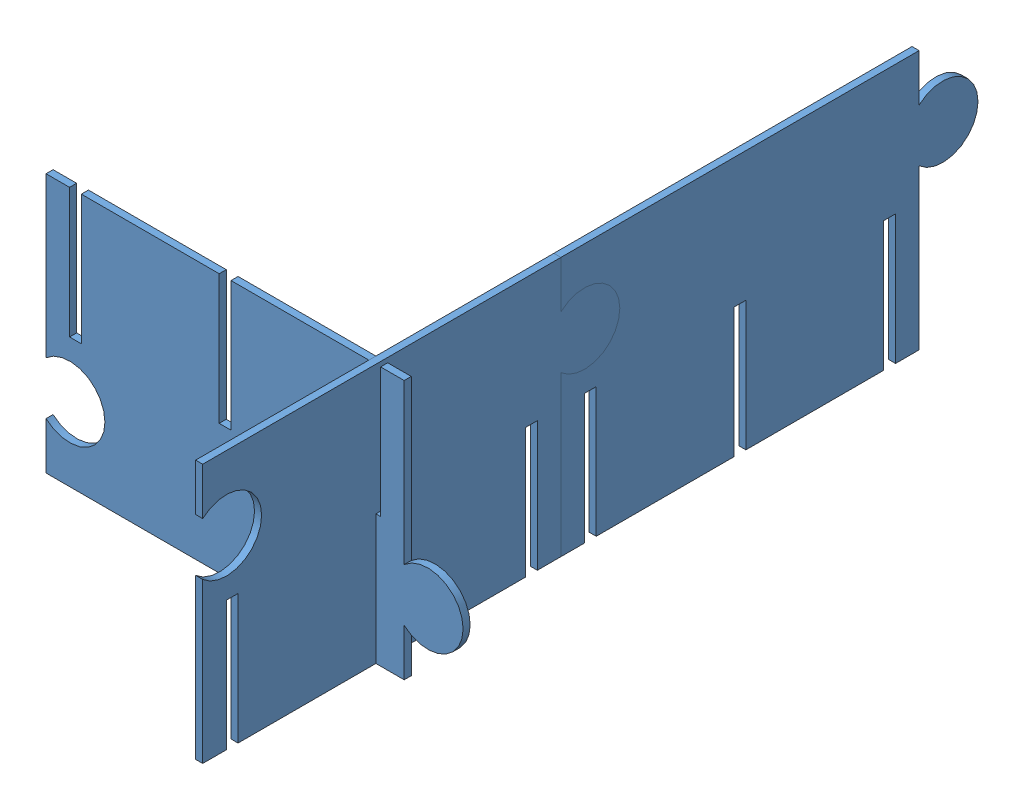
SolidWorks assembly Assemblage1, configuration Défaut. Lengths in mm.
Overall size (177 110 329).
3 component instances, 1 part files, 5 mates.
Components (placement in the parent):
- projet mur cit-1: projet mur cit [Défaut] at (-158.0764 -6.6817 151.155) size (3 110 177)
- projet mur cit-2: projet mur cit [Défaut] at (-158.0764 -6.6817 -0.845) size (3 110 177)
- projet mur cit-3: projet mur cit [Défaut] at (-275.0672 57.5391 97.6642) x (0 0 -1) z (-1 0 0) size (3 110 177)
Mates (geometry in assembly coordinates):
- Coïncidente1: coincident: circle of projet mur cit-1; circle of projet mur cit-2
- Coïncidente2: coincident: plane of projet mur cit-1 through (-155.0764 80.4287 19.1642) normal (0 0 -1); plane of projet mur cit-2 through (-155.0764 80.4287 19.1642) normal (0 0 1)
- Coïncidente4: coincident: line of projet mur cit-1 through (-158.0764 -29.5713 97.6642) axis (0 1 0); line of projet mur cit-3 through (-158.0764 -31.6037 97.6642) axis (0 -1 0)
- Coïncidente5: coincident: plane of projet mur cit-1 through (-155.0764 -29.5713 97.6642) normal (0 0 -1); plane of projet mur cit-3 through (-133.0764 1.609 97.6642) normal (0 0 1)
- Coïncidente6: coincident: plane of projet mur cit-1 through (-155.0764 25.4287 97.6642) normal (0 -1 0); plane of projet mur cit-3 through (-158.0764 25.4287 94.6642) normal (0 1 0)
